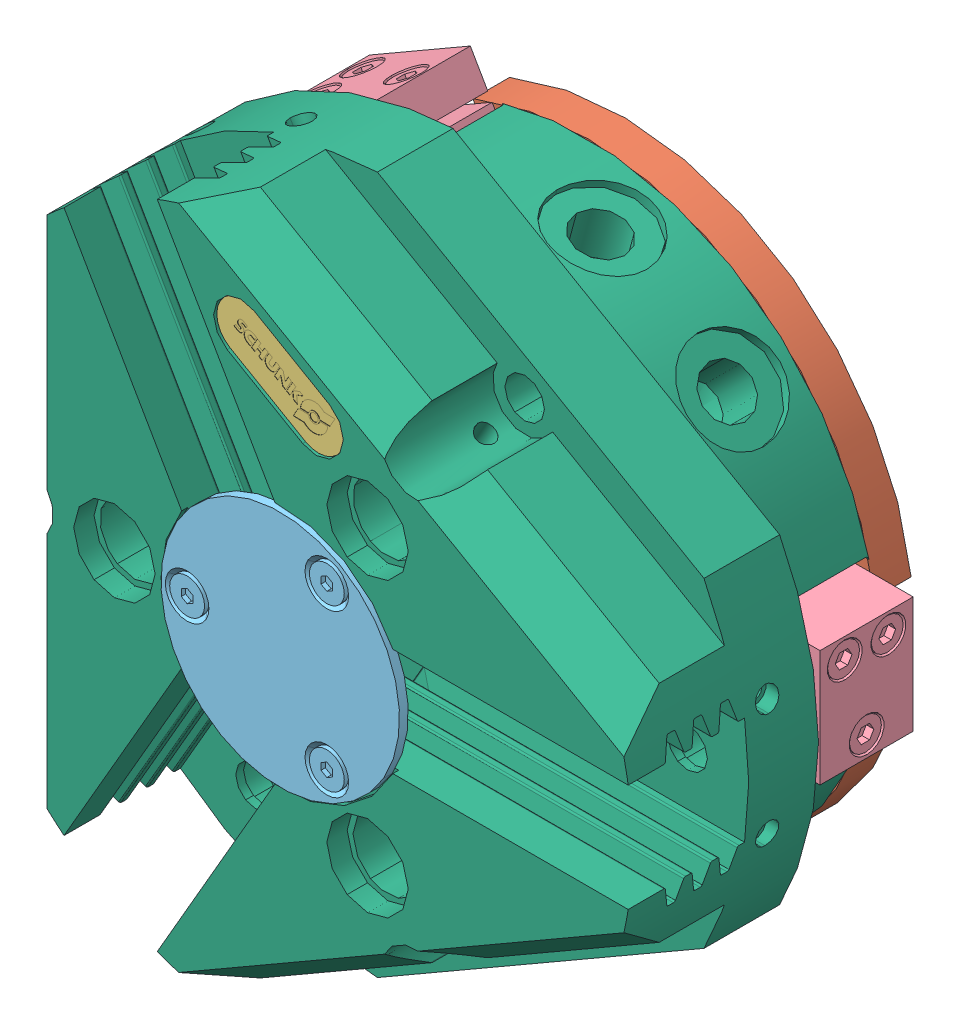
SolidWorks assembly SCHUNK_0303312_PZN_plus_100_1__00000, configuration Default. Lengths in mm.
Overall size (159.06 155.63 58.8).
8 component instances, 6 part files, 0 mates.
Components (placement in the parent):
- SCHUNK_0303312_PZN_plus_100_1__00000_3-1: SCHUNK_0303312_PZN_plus_100_1__00000_3 [Default] at (-39.3115 -15.8193 29.8) x (0.374607 -0.927184 0) z (0 0 -1) size (3.8 2.96 5)
- SCHUNK_0303312_PZN_plus_100_1__00000_9-1: SCHUNK_0303312_PZN_plus_100_1__00000_9 [Default] at (0 0 6.3) x (0.866025 -0.5 0) z (0.5 0.866025 0) size (100 6.3 99.61)
- SCHUNK_0303312_PZN_plus_100_1__00000_11-1: SCHUNK_0303312_PZN_plus_100_1__00000_11 [Default] at (-0.8084 39.8998 57.6) x (0.866025 -0.5 0) z (0 0 1) size (24 9 0.3)
- SCHUNK_0303312_PZN_plus_100_1__00000_13-1: SCHUNK_0303312_PZN_plus_100_1__00000_13 [Default] at (44.5 0 6.55) x (1 0 0) z (0 -1 0) size (12 16 20)
- SCHUNK_0303312_PZN_plus_100_1__00000_13-2: SCHUNK_0303312_PZN_plus_100_1__00000_13 [Default] at (-22.25 -38.5381 6.55) x (-0.5 -0.866025 0) z (-0.866025 0.5 0) size (12 16 20)
- SCHUNK_0303312_PZN_plus_100_1__00000_13-3: SCHUNK_0303312_PZN_plus_100_1__00000_13 [Default] at (-22.25 38.5381 6.55) x (-0.5 0.866025 0) z (0.866025 0.5 0) size (12 16 20)
- SCHUNK_0303312_PZN_plus_100_1__00000_17-1: SCHUNK_0303312_PZN_plus_100_1__00000_17 [Default] at (0 0 57.3) x (0.5 0.866025 0) z (0.866025 -0.5 0) size (41 1.5 41)
- SCHUNK_0303312_PZN_plus_100_1__00000_19-1: SCHUNK_0303312_PZN_plus_100_1__00000_19 [Default] at (0 0 6.3) x (-0.866025 0.5 0) z (0.5 0.866025 0) size (119.87 52 110.5)
